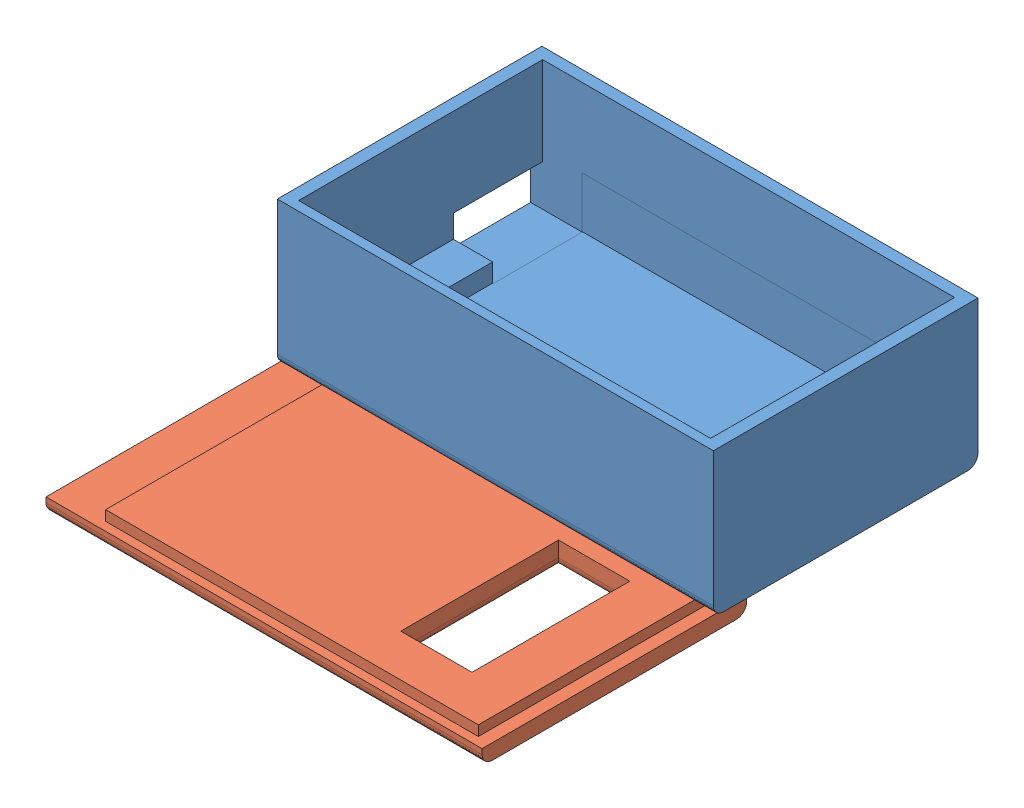
SolidWorks assembly Assem1, configuration Default. Lengths in mm.
Overall size (130.88 61.38 101.72).
2 component instances, 2 part files, 0 mates.
Components (placement in the parent):
- ECE101 Final CAD-2: ECE101 Final CAD [Default] at (29.871 39.2734 95.8078) size (108.82 36.07 66.04)
- ECE 101 Final CAD- Lid-2: ECE 101 Final CAD- Lid [Default] at (7.8201 13.962 131.49) size (108.82 6.35 66.04)
